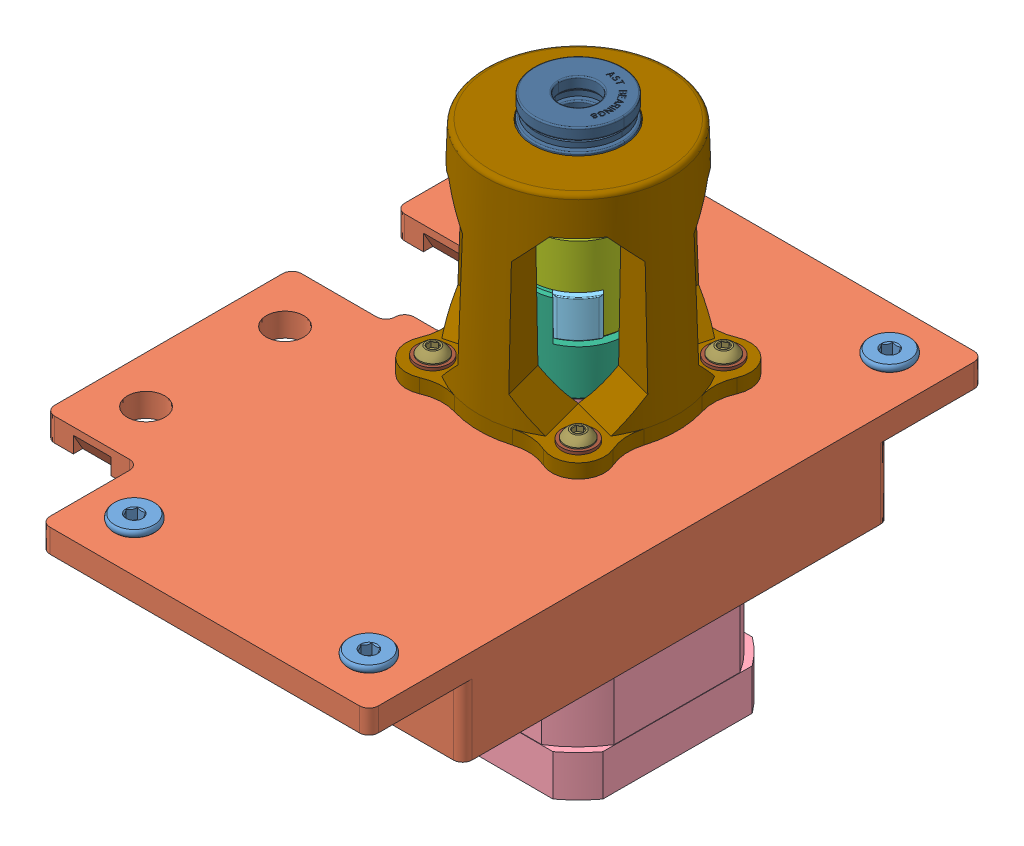
SolidWorks assembly front_left_z_plate_assembly, configuration Default. Lengths in mm.
Overall size (90 112 131).
27 component instances, 12 part files, 3 mates.
Components (placement in the parent):
- m5_low_profile_screw_template_M5 x 10-1: m5_low_profile_screw_template_M5 x 10 [Default] at (-44.929 19.0105 493.3157) x (0 -1 0) z (0 0 1) size (11.62 9 9)
- m5_low_profile_screw_template_M5 x 10-2: m5_low_profile_screw_template_M5 x 10 [Default] at (5.071 19.0105 493.3157) x (0 -1 0) z (0 0 1) size (11.62 9 9)
- m5_low_profile_screw_template_M5 x 10-3: m5_low_profile_screw_template_M5 x 10 [Default] at (5.071 19.0105 382.3157) x (0 -1 0) z (0 0 1) size (11.62 9 9)
- m5_low_profile_screw_template_M5 x 10-4: m5_low_profile_screw_template_M5 x 10 [Default] at (-64.929 19.0105 382.3157) x (0 -1 0) z (0 0 1) size (11.62 9 9)
- front_z_panel_v2_Front Left Z Motor Plate-1: front_z_panel_v2_Front Left Z Motor Plate [Default] at (-74.929 24.0105 503.3157) size (90 20 131)
- m5_locking_t_nut_20x20_generic-1: m5_locking_t_nut_20x20_generic [Default] at (-44.929 19.0105 490.3157) size (10 4.5 6)
- m5_locking_t_nut_20x20_generic-2: m5_locking_t_nut_20x20_generic [Default] at (5.071 19.0105 490.3157) size (10 4.5 6)
- m5_locking_t_nut_20x20_generic-3: m5_locking_t_nut_20x20_generic [Default] at (-64.929 19.0105 379.3157) size (10 4.5 6)
- m5_locking_t_nut_20x20_generic-4: m5_locking_t_nut_20x20_generic [Default] at (5.071 19.0105 379.3157) size (10 4.5 6)
- Copy of z_motor_thrust_assy_printed^front_left_z_plate_assembly-1: Copy of z_motor_thrust_assy_printed^front_left_z_plate_assembly [Default] at (-143.9551 -0.0004 401.3583) x (0.999997 0 0.002418) z (-0.002418 0 0.999997) size (42.42 112 42.42) (virtual)
  - z_motor_thrust_coupling_assembly_3-1: z_motor_thrust_coupling_assembly_3 [Default] at (547.6945 -11.7621 -290.9574) x (0 0 1) z (-1 0 0) size (42.42 92 42.42)
    - 17HM19-2004S-1: 17HM19-2004S [Default] at (307.9646 28.773 428.6645) x (0 0 -1) z (0 1 0) size (42.42 42.42 72)
    - couplings_cajc20-rd-5-8-1: couplings_cajc20-rd-5-8 [Default] at (307.9646 57.773 428.6645) x (0 1 0) z (0 0 1) size (30 20 20)
      - couplings_cajc20-rd-5-8_01-1: couplings_cajc20-rd-5-8_01 [Default] at origin size (8 18.12 18.12)
      - couplings_cajc20-rd-5-8_02-1: couplings_cajc20-rd-5-8_02 [Default] at origin size (19 20 19.99)
      - couplings_cajc20-rd-5-8_03-1: couplings_cajc20-rd-5-8_03 [Default] at origin size (19 19.99 20)
  - NEMA17_spacer_plate_7mm-1: NEMA17_spacer_plate_7mm [Default] at (119.03 24.0109 17.0072) x (-1 0 0) z (0 -1 0) size (42.3 42.3 7)
  - thrust_cage-1: thrust_cage [Default] at (119.03 44.6637 17.0072) x (0.002418 0 0.999997) z (-0.999997 0 0.002418) size (42.3 47 42.3)
  - AST_Bearings_F8-19M-1: AST_Bearings_F8-19M [Default] at (119.03 77.5109 17.0072) x (0.99905 0 -0.043582) z (0.043582 0 0.99905) size (19 7 19)
  - m3_stainless_steel_washer_90965A130-1: m3_stainless_steel_washer_90965A130 [90965A130] at (134.5301 32.0109 1.5071) x (1 0 0) z (0 1 0) size (7 7 0.6)
  - m3_stainless_steel_washer_90965A130-2: m3_stainless_steel_washer_90965A130 [90965A130] at (134.605 32.0109 32.5071) x (1 0 -0.000026) z (0 1 0) size (7 7 0.6)
  - m3_stainless_steel_washer_90965A130-3: m3_stainless_steel_washer_90965A130 [90965A130] at (103.5301 32.0109 1.5821) x (1 0 0) z (0 1 0) size (7 7 0.6)
  - m3_stainless_steel_washer_90965A130-4: m3_stainless_steel_washer_90965A130 [90965A130] at (103.6051 32.0109 32.582) x (1 0 0) z (0 1 0) size (7 7 0.6)
  - m3_20mm_buttohead_screw_92095A185-1: m3_20mm_buttohead_screw_92095A185 [92095A185] at (103.5301 34.2609 1.5821) x (1 0 0) z (0 1 0) size (5.7 5.7 21.83)
  - m3_20mm_buttohead_screw_92095A185-2: m3_20mm_buttohead_screw_92095A185 [92095A185] at (103.6051 34.2609 32.582) x (1 0 0) z (0 1 0) size (5.7 5.7 21.83)
  - m3_20mm_buttohead_screw_92095A185-3: m3_20mm_buttohead_screw_92095A185 [92095A185] at (134.5301 34.2609 1.5071) x (1 0 0) z (0 1 0) size (5.7 5.7 21.83)
  - m3_20mm_buttohead_screw_92095A185-4: m3_20mm_buttohead_screw_92095A185 [92095A185] at (134.605 34.2609 32.5071) x (1 0 0) z (0 1 0) size (5.7 5.7 21.83)
Mates (geometry in assembly coordinates):
- Coincident1: coincident anti-aligned: plane of front_z_panel_v2_Front Left Z Motor Plate-1 through (-74.929 24.0105 503.3157) normal (0 -1 0); plane of Copy of z_motor_thrust_assy_printed^front_left_z_plate_assembly-1/NEMA17_spacer_plate_7mm-1 through (-24.9665 24.0105 418.6533) normal (0 1 0)
- Concentric2: concentric aligned: cylinder of front_z_panel_v2_Front Left Z Motor Plate-1 through (-40.429 24.0095 403.1907) axis (0 1 0) radius 1.7; circle of Copy of z_motor_thrust_assy_printed^front_left_z_plate_assembly-1/m3_20mm_buttohead_screw_92095A185-1
- Concentric3: concentric aligned: cylinder of front_z_panel_v2_Front Left Z Motor Plate-1 through (-40.429 24.0095 434.1907) axis (0 1 0) radius 1.7; circle of Copy of z_motor_thrust_assy_printed^front_left_z_plate_assembly-1/m3_20mm_buttohead_screw_92095A185-2
